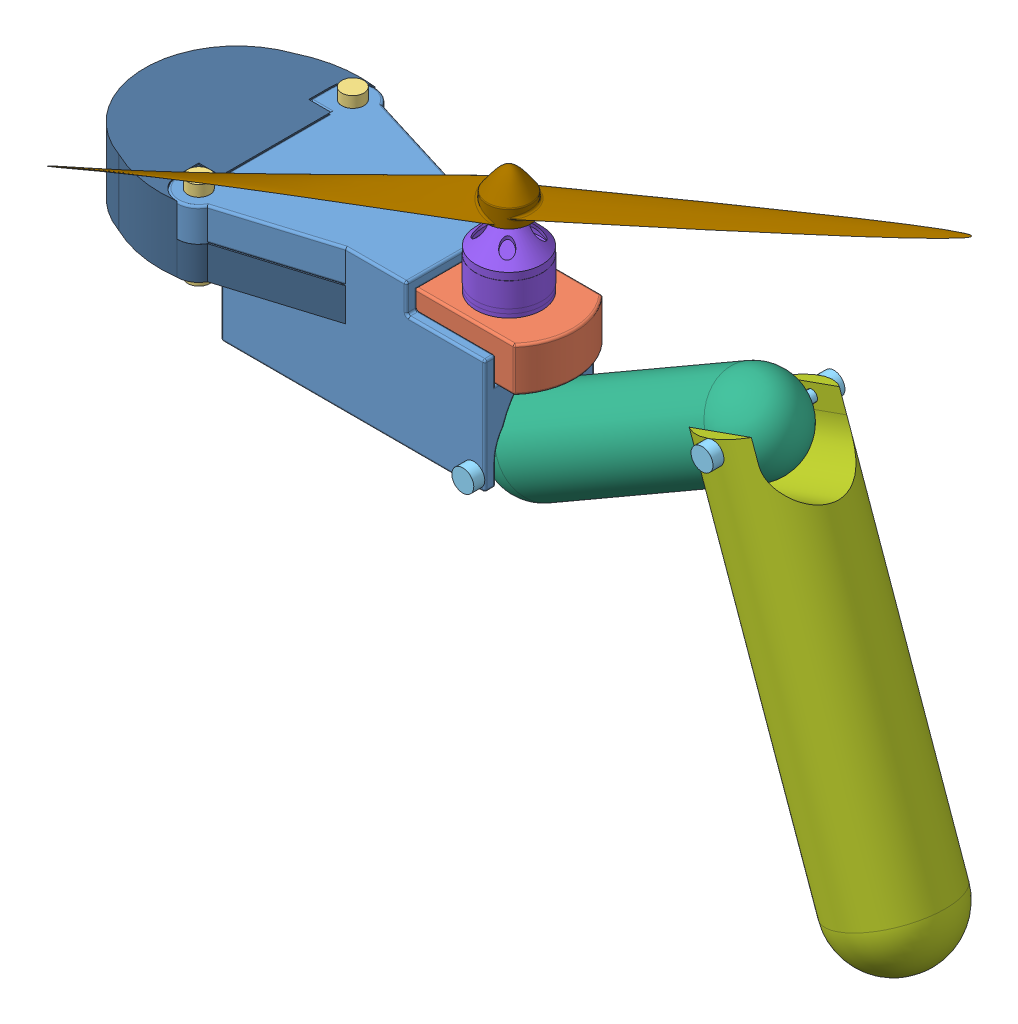
SolidWorks assembly Sistema de brazo V2, configuration Predeterminado. Lengths in mm.
Overall size (372.38 235.23 205.09).
12 component instances, 10 part files, 26 mates.
Components (placement in the parent):
- Brazo1-1: Brazo1 [Predeterminado] at (-6.6953 0.9378 140) size (130.88 65.06 90)
- Brazo2-1: Brazo2 [Predeterminado] at (-20.6953 5.9378 140) size (180.03 20 40)
- UnionB1Cuerpo-1: UnionB1Cuerpo [Predeterminado] at (-66.6953 15.9378 105) x (0 1 0) z (0 0 1) size (40 10 10)
- UnionB1Cuerpo-2: UnionB1Cuerpo [Predeterminado] at (-66.6953 15.9378 175) x (0 1 0) z (-0.093327 0 0.995636) size (40 10 10)
- TornilloSinFin-1: TornilloSinFin [Predeterminado] at (-26.6953 14.2204 138.1832) x (-1 0 0) z (0 0.686954 0.726701) size (180.05 11.57 10.06)
- UnionB1P1-1: UnionB1P1 [Predeterminado] at (48.3047 -29.0622 140) x (0 0 -1) z (0.999335 0.036466 0) size (60 10 10)
- Pierna1V2-1: Pierna1V2 [Predeterminado] at (165.0941 38.3661 140) x (-0.866025 -0.5 0) z (0 0 1) size (150 40 40)
- Pierna2V2-2: Pierna2V2 [Predeterminado] at (209.6756 -114.1116 140) x (-0.33546 0.942054 0) z (0 0 1) size (200 50 50)
- UnionB1P1-2: UnionB1P1 [Predeterminado] at (157.0358 33.7137 140) x (0 0 1) z (0.770088 -0.637938 0) size (60 10 10)
- Motor-1: Motor [Predeterminado] at (39.3047 35.1507 140) x (0.664179 0 0.747574) z (-0.747574 0 0.664179) size (30.15 36.5 30.15)
- Helise-1: Helise [Predeterminado] at (39.3047 61.4393 140) x (0.608985 0 0.793182) z (-0.793182 0 0.608985) size (28.24 20.07 300)
- Pinza-1: Pinza [Predeterminado] at (-75.6905 0.9378 140) size (116.44 30 90.88)
Mates (geometry in assembly coordinates):
- Coincidente1: coincident anti-aligned: plane of Brazo1-1 through (-101.4166 25.9378 160) normal (0 0 -1); plane of Brazo2-1 through (-110.6953 25.9378 160) normal (0 0 1)
- Coincidente2: coincident anti-aligned: plane of Brazo1-1 through (-101.4166 25.9378 160) normal (0 -1 0); plane of Brazo2-1 through (39.3047 25.9378 140) normal (0 1 0)
- Concéntrica20: concentric anti-aligned: cylinder of Brazo1-1 through (-66.6953 0.9368 105) axis (0 1 0) radius 5; cylinder of UnionB1Cuerpo-1 through (-66.6953 -23.5642 105) axis (0 -1 0) radius 2.5
- Coincidente7: coincident anti-aligned: plane of Brazo1-1 through (-6.6953 30.9378 140) normal (0 1 0); plane of UnionB1Cuerpo-1 through (-66.6953 30.9378 102.5) normal (0 -1 0)
- Concéntrica21: concentric anti-aligned: circle of Brazo1-1; cylinder of UnionB1Cuerpo-2 through (-66.6953 -23.5642 175) axis (0 -1 0) radius 2.5
- Coincidente8: coincident anti-aligned: plane of Brazo1-1 through (-6.6953 30.9378 140) normal (0 1 0); plane of UnionB1Cuerpo-2 through (-66.4619 30.9378 172.5109) normal (0 -1 0)
- Concéntrica22: concentric anti-aligned: circle of Brazo2-1; circle of TornilloSinFin-1
- Coincidente12: coincident anti-aligned: plane of Pinza-1 through (-111.6953 0.9378 140) normal (1 0 0); plane of TornilloSinFin-1 through (-111.6953 14.2204 138.1832) normal (-1 0 0)
- Distancia límite1: limit distance = 1 mm anti-aligned: plane of Pinza-1 through (-111.6953 0.9378 140) normal (1 0 0); plane of Brazo2-1 through (-110.6953 25.9378 120) normal (-1 0 0)
- Concéntrica24: concentric anti-aligned: cylinder of Brazo1-1 through (48.3047 -29.0622 172.0711) axis (0 0 -1) radius 2.5; cylinder of UnionB1P1-1 through (48.3047 -29.0622 179.502) axis (0 0 1) radius 2.5
- Concéntrica32: concentric anti-aligned: cylinder of Brazo1-1 through (48.3047 -29.0622 172.0711) axis (0 0 -1) radius 2.5; cylinder of Pierna1V2-1 through (48.3047 -29.0622 120) axis (0 0 1) radius 2.5
- Coincidente20: coincident anti-aligned: circle of Brazo1-1; circle of UnionB1P1-1
- Concéntrica33: concentric aligned: cylinder of Pierna1V2-1 through (157.0358 33.7137 120) axis (0 0 1) radius 2.5; cylinder of Pierna2V2-2 through (157.0358 33.7137 115) axis (0 0 1) radius 2.5
- Concéntrica34: concentric anti-aligned: cylinder of Pierna2V2-2 through (157.0358 33.7137 115) axis (0 0 1) radius 2.5; cylinder of UnionB1P1-2 through (157.0358 33.7137 100.498) axis (0 0 -1) radius 2.5
- Ángulo límite9: limit planar angle = 3.665191 rad anti-aligned: cylinder of Brazo1-1 through (-66.6953 -24.0622 140) axis (1 0 0) radius 20; cylinder of Pierna1V2-1 through (219.7275 69.9088 140) axis (0.866025 0.5 0) radius 20
- Ángulo límite8: limit planar angle = 4.893894 rad anti-aligned: cylinder of Pierna2V2-2 through (222.4506 -149.9869 140) axis (0.33546 -0.942054 0) radius 25; cylinder of Pierna1V2-1 through (219.7275 69.9088 140) axis (0.866025 0.5 0) radius 20
- Coincidente21: coincident anti-aligned: plane of Brazo2-1 through (39.3047 25.9378 140) normal (0 1 0); plane of Motor-1 through (39.3047 25.9378 140) normal (0 -1 0)
- Concéntrica35: concentric aligned: cylinder of Brazo2-1 through (39.3047 25.9378 140) axis (0 -1 0) radius 30; cylinder of Motor-1 through (39.3047 24.4859 140) axis (0 -1 0) radius 15
- Bloquear1: lock: unknown of Brazo2-1; unknown of Motor-1
- Coincidente22: coincident anti-aligned: plane of Motor-1 through (39.3047 62.4393 140) normal (0 1 0); plane of Helise-1 through (39.3047 62.4393 140) normal (0 -1 0)
- Concéntrica36: concentric aligned: cylinder of Motor-1 through (39.3047 62.4393 140) axis (0 -1 0) radius 1; cylinder of Helise-1 through (39.3047 62.4393 140) axis (0 -1 0) radius 1
- Concéntrica40: concentric aligned: cylinder of UnionB1Cuerpo-2 through (-66.6953 -23.5642 175) axis (0 -1 0) radius 2.5; cylinder of Pinza-1 through (-66.6953 15.9378 175) axis (0 -1 0) radius 2.5
- Coincidente24: coincident anti-aligned: plane of UnionB1Cuerpo-2 through (-66.4619 0.9378 172.5109) normal (0 1 0); plane of Pinza-1 through (-75.6953 0.9378 140) normal (0 -1 0)
- Concéntrica41: concentric aligned: cylinder of UnionB1Cuerpo-1 through (-66.6953 -23.5642 105) axis (0 -1 0) radius 2.5; cylinder of Pinza-1 through (-66.6953 15.9378 105) axis (0 -1 0) radius 2.5
- Tangente1: tangent anti-aligned: plane of Brazo1-1 through (-66.6953 -34.0622 160) normal (0 0 -1); sphere of Pierna1V2-1
- Tangente2: tangent anti-aligned: sphere of Pierna1V2-1; plane of Pierna2V2-2 through (182.2645 37.3899 160) normal (0 0 -1)
